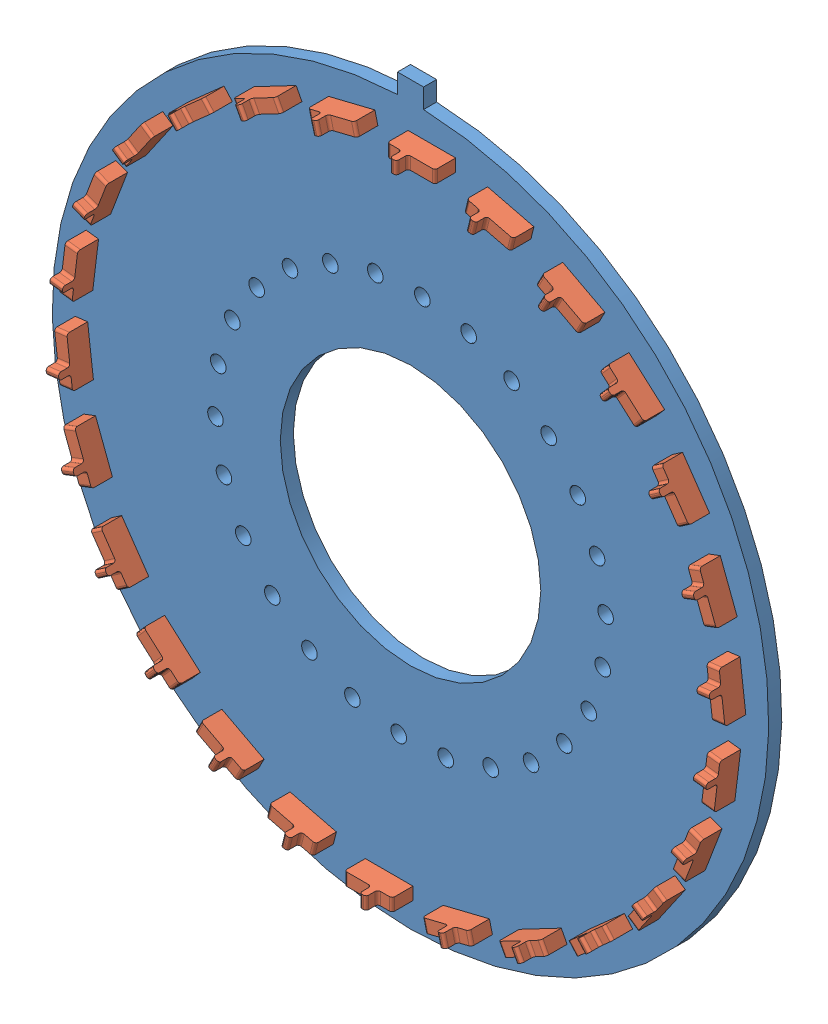
SolidWorks assembly PCB assembly, configuration Default. Lengths in mm.
Overall size (67.78 70.24 3.5).
27 component instances, 2 part files, 1 mates.
Components (placement in the parent):
- selector wheel PCB-2: selector wheel PCB [Default] at (5.7522 55.5231 3.5161) size (67.78 70.24 1)
- spring pin-27: spring pin [Default] at (7.3927 81.0239 5.3161) x (1 0 0) z (0 -1 0) size (3.66 2.5 0.96)
- spring pin-28: spring pin [Default] at (1.2423 80.6755 5.3161) x (0.970942 0.239316 0) z (0.239316 -0.970942 0) size (3.66 2.5 0.96)
- spring pin-29: spring pin [Default] at (-4.6461 78.8653 5.3161) x (0.885456 0.464723 0) z (0.464723 -0.885456 0) size (3.66 2.5 0.96)
- spring pin-30: spring pin [Default] at (-9.9301 75.6986 5.3161) x (0.748511 0.663123 0) z (0.663123 -0.748511 0) size (3.66 2.5 0.96)
- spring pin-31: spring pin [Default] at (-14.3027 71.3593 5.3161) x (0.568065 0.822984 0) z (0.822984 -0.568065 0) size (3.66 2.5 0.96)
- spring pin-32: spring pin [Default] at (-17.5098 66.0997 5.3161) x (0.354605 0.935016 0) z (0.935016 -0.354605 0) size (3.66 2.5 0.96)
- spring pin-33: spring pin [Default] at (-19.365 60.2254 5.3161) x (0.120537 0.992709 0) z (0.992709 -0.120537 0) size (3.66 2.5 0.96)
- spring pin-34: spring pin [Default] at (-19.7605 54.0778 5.3161) x (-0.120537 0.992709 0) z (0.992709 0.120537 0) size (3.66 2.5 0.96)
- spring pin-35: spring pin [Default] at (-18.6732 48.0142 5.3161) x (-0.354605 0.935016 0) z (0.935016 0.354605 0) size (3.66 2.5 0.96)
- spring pin-36: spring pin [Default] at (-16.1665 42.3871 5.3161) x (-0.568065 0.822984 0) z (0.822984 0.568065 0) size (3.66 2.5 0.96)
- spring pin-37: spring pin [Default] at (-12.3859 37.5233 5.3161) x (-0.748511 0.663123 0) z (0.663123 0.748511 0) size (3.66 2.5 0.96)
- spring pin-38: spring pin [Default] at (-7.5512 33.7056 5.3161) x (-0.885456 0.464723 0) z (0.464723 0.885456 0) size (3.66 2.5 0.96)
- spring pin-39: spring pin [Default] at (-1.9434 31.1559 5.3161) x (-0.970942 0.239316 0) z (0.239316 0.970942 0) size (3.66 2.5 0.96)
- spring pin-40: spring pin [Default] at (4.1117 30.0223 5.3161) x (-1 0 0) z (0 1 0) size (3.66 2.5 0.96)
- spring pin-41: spring pin [Default] at (10.2621 30.3707 5.3161) x (-0.970942 -0.239316 0) z (-0.239316 0.970942 0) size (3.66 2.5 0.96)
- spring pin-42: spring pin [Default] at (16.1505 32.1809 5.3161) x (-0.885456 -0.464723 0) z (-0.464723 0.885456 0) size (3.66 2.5 0.96)
- spring pin-43: spring pin [Default] at (21.4345 35.3476 5.3161) x (-0.748511 -0.663123 0) z (-0.663123 0.748511 0) size (3.66 2.5 0.96)
- spring pin-44: spring pin [Default] at (25.8071 39.6869 5.3161) x (-0.568065 -0.822984 0) z (-0.822984 0.568065 0) size (3.66 2.5 0.96)
- spring pin-45: spring pin [Default] at (29.0142 44.9465 5.3161) x (-0.354605 -0.935016 0) z (-0.935016 0.354605 0) size (3.66 2.5 0.96)
- spring pin-46: spring pin [Default] at (30.8694 50.8208 5.3161) x (-0.120537 -0.992709 0) z (-0.992709 0.120537 0) size (3.66 2.5 0.96)
- spring pin-47: spring pin [Default] at (31.2649 56.9684 5.3161) x (0.120537 -0.992709 0) z (-0.992709 -0.120537 0) size (3.66 2.5 0.96)
- spring pin-48: spring pin [Default] at (30.1776 63.032 5.3161) x (0.354605 -0.935016 0) z (-0.935016 -0.354605 0) size (3.66 2.5 0.96)
- spring pin-49: spring pin [Default] at (27.6709 68.6591 5.3161) x (0.568065 -0.822984 0) z (-0.822984 -0.568065 0) size (3.66 2.5 0.96)
- spring pin-50: spring pin [Default] at (23.8903 73.5229 5.3161) x (0.748511 -0.663123 0) z (-0.663123 -0.748511 0) size (3.66 2.5 0.96)
- spring pin-51: spring pin [Default] at (19.0556 77.3406 5.3161) x (0.885456 -0.464723 0) z (-0.464723 -0.885456 0) size (3.66 2.5 0.96)
- spring pin-52: spring pin [Default] at (13.4478 79.8903 5.3161) x (0.970942 -0.239316 0) z (-0.239316 -0.970942 0) size (3.66 2.5 0.96)
Mates (geometry in assembly coordinates):
- Coincident1: coincident anti-aligned: plane of selector wheel PCB-2 through (5.7522 55.5231 4.5161) normal (0 0 1); plane of spring pin-27 through (5.5627 80.0639 4.5161) normal (0 0 -1)
